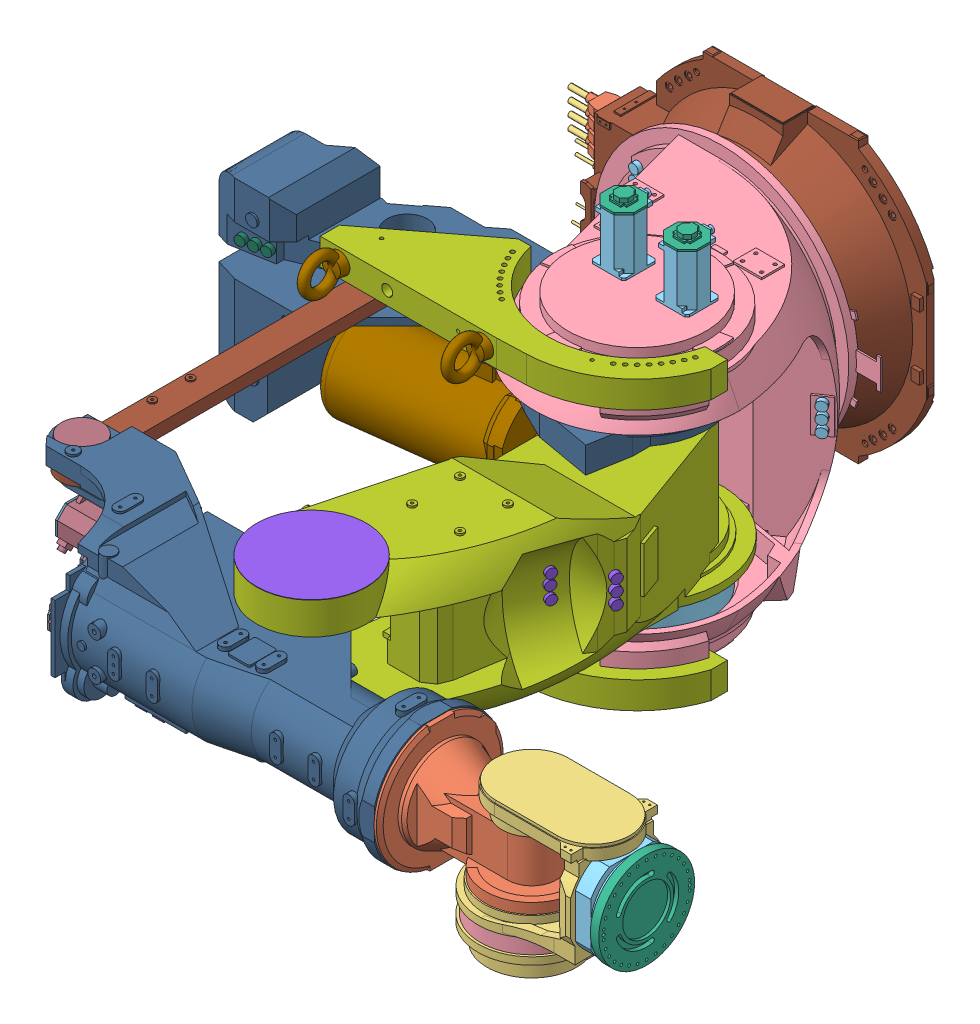
SolidWorks assembly 3D_M-2000iA_2300_v02, configuration По умолчанию. Lengths in mm.
Overall size (3899.6 2081.6 3681).
33 component instances, 29 part files, 0 mates.
Components (placement in the parent):
- ST201_darkgray-1: ST201_darkgray [По умолчанию] at (-777.6 365 12) x (-1 0 0) z (0 0 1) size (2.6 730 232.5)
- ST201_white-1: ST201_white [По умолчанию] at (-777.6 365 12) x (-1 0 0) z (0 0 1) size (142 660.5 140)
- ST201_black-1: ST201_black [По умолчанию] at (-777.6 365 12) x (-1 0 0) z (0 0 1) size (242 618 119)
- ST301_yellow-1: ST301_yellow [По умолчанию] at origin size (1740.26 1446 1566.84)
- J2_black-1: J2_black [По умолчанию] at origin size (1280.31 1999 1260)
- J2_red-1: J2_red [По умолчанию] at origin size (1164.41 2081.6 413.5)
- J2arm_yellow_2-1: J2arm_yellow_2 [По умолчанию] at (500 0 1300) size (1041.3 939 2427)
- SV301_link-1: SV301_link [По умолчанию] at (0 -12 0) size (860.35 80 212.86)
- SV301-1: SV301 [По умолчанию] at (0 -12 0) size (1084.98 604 566.43)
- SX317-1: SX317 [По умолчанию] at (500 0 1300) size (2240 1056 961.9)
- ST324-1: ST324 [По умолчанию] at (-700 219 1300) size (230 100 1930)
- Shaft1-1: Shaft1 [По умолчанию] at (-704.104 121 1297.2185) x (1 0 0) z (0 0 -1) size (211 196 211)
- J3_black-1: J3_black [По умолчанию] at (500 0 3000) size (615.5 694.51 495.24)
- J3_red-1: J3_red [По умолчанию] at (500 0 3000) size (83.3 621.56 303.19)
- counter stopper-1: counter stopper [По умолчанию] at origin size (171.76 50 54.14)
- J3_connector_yellow-1: J3_connector_yellow [По умолчанию] at (82 -317 3438) x (-1 0 0) z (0 0 1) size (310 2 130)
- J3_connector_white-1: J3_connector_white [По умолчанию] at (170.5 -315 3438.25) size (171.5 28.5 43)
- J3_connector_bronze-1: J3_connector_bronze [По умолчанию] at (166 -337 3241) x (1 0 0) z (0 0 -1) size (74 18 27.71)
- ST201_bronze-1: ST201_bronze [По умолчанию] at (-777.6 383 18) x (-1 0 0) z (0 0 1) size (18 89 27.71)
- SX501-1: SX501 [По умолчанию] at (1514 0 3350) size (739 652 662)
- ST511_yellow-1: ST511_yellow [По умолчанию] at (2000 0 3350) size (798 735 562)
- ST511_black-1: ST511_black [По умолчанию] at (2000 0 3350) size (536 85 536)
- J6_RV-1: J6_RV [По умолчанию] at (2440.2 0 3350) x (0 0 -1) z (0 -1 0) size (425 124 425)
- SX551-1: SX551 [По умолчанию] at (2564.2 0 3350) size (44 500 500)
- SX273-1: SX273 [По умолчанию] at (500 -750 1300) size (1621 140 505)
- SX273-2: SX273 [По умолчанию] at (500 610 1300) size (1621 140 505)
- J2arm_black_2-1: J2arm_black_2 [По умолчанию] at (500 0 1300) size (881.53 778 1330.15)
- LIBRL_JB-BEY-64-1: LIBRL_JB-BEY-64 [По умолчанию] at (-450 -680 1905) x (0 1 0) z (0 0 1) size (210 110 294)
- LIBRL_JB-BEY-64-2: LIBRL_JB-BEY-64 [По умолчанию] at (-450 680 1905) x (0 1 0) z (0 0 1) size (210 110 294)
- LIBRL_JB-BEY-64-3: LIBRL_JB-BEY-64 [По умолчанию] at (300 680 1905) x (0 -1 0) z (0 0 1) size (210 110 294)
- LIBRL_JB-BEY-64-4: LIBRL_JB-BEY-64 [По умолчанию] at (300 -680 1905) x (0 -1 0) z (0 0 1) size (210 110 294)
- ST401_2-1: ST401_2 [По умолчанию] at (500 0 3000) size (2329 743.51 826)
- ST201_gray_2-1: ST201_gray_2 [По умолчанию] at origin size (1540 1480 345)
